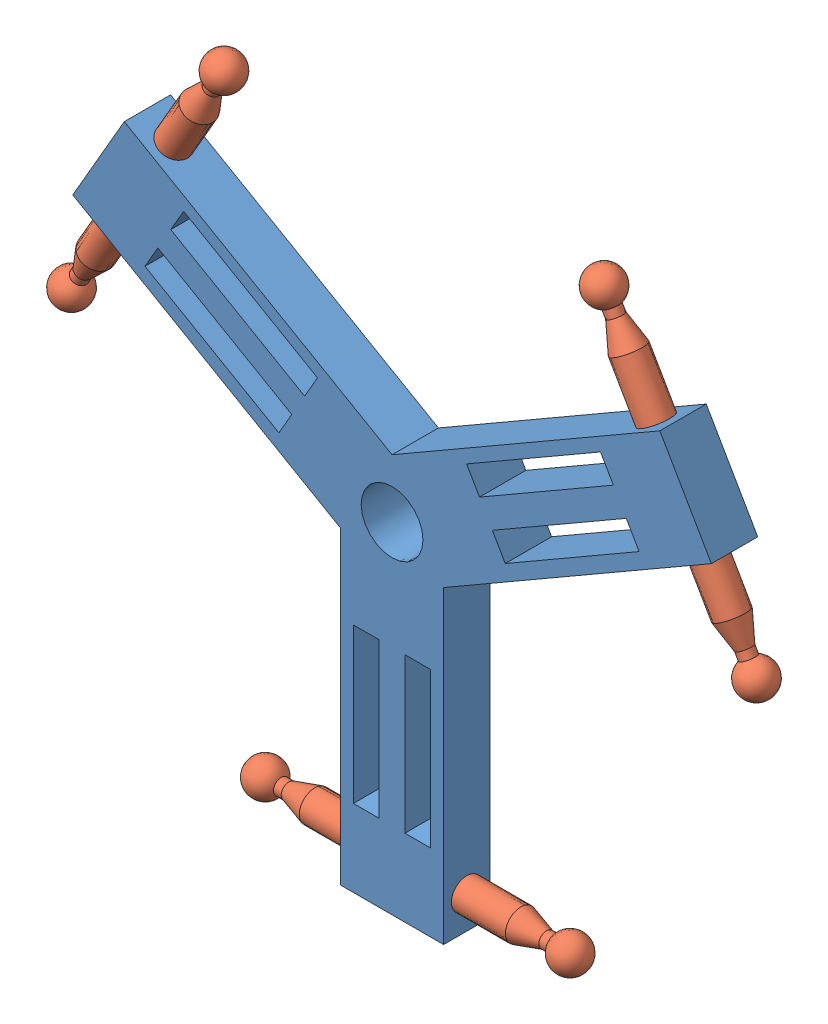
SolidWorks assembly Assem3, configuration Default. Lengths in mm.
Overall size (1423.4 1265.62 90).
4 component instances, 2 part files, 2 mates.
Components (placement in the parent):
- part 6-1: part 6 [Default] at (597.5949 740.1294 855.3241) size (1239.23 1073.21 90)
- link 2-1: link 2 [Default] at (602.4409 143.5269 900.3241) x (1 0 0) z (0 -0.01299 0.999916) size (660 68.46 68.46)
- link 2-2: link 2 [Default] at (1111.8448 1042.6275 900.3241) x (-0.5 0.866025 0) z (0.011249 0.006495 0.999916) size (660 68.46 68.46)
- link 2-3: link 2 [Default] at (78.4989 1034.2339 900.3241) x (-0.5 -0.866025 0) z (-0.011249 0.006495 0.999916) size (660 68.46 68.46)
Mates (geometry in assembly coordinates):
- Concentric1: concentric: cylinder of part 6-1 through (-22.0204 143.5269 900.3241) axis (1 0 0) radius 30; cylinder of link 2-1 through (337.4409 143.5269 900.3241) axis (-1 0 0) radius 30
- Lock1: lock: unknown of part 6-1; unknown of link 2-1
